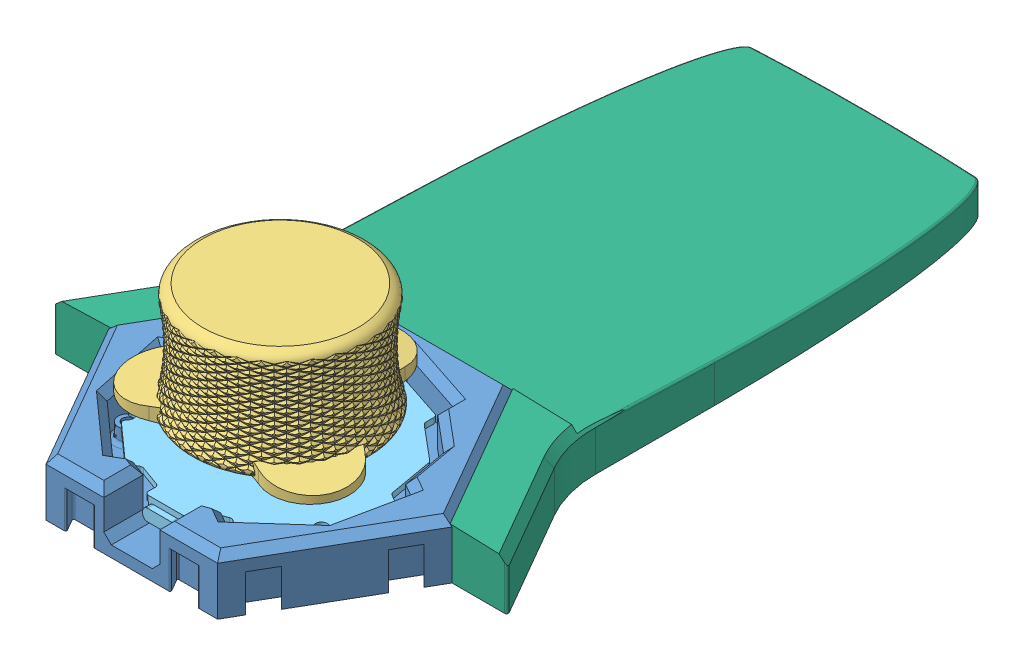
SolidWorks assembly Assembly, configuration Default. Lengths in mm.
Overall size (121.27 58.2 198.02).
6 component instances, 6 part files, 15 mates.
Components (placement in the parent):
- Base-1: Base [Default] at (5.116 33.8502 100.9363) size (92 26.6 79.67)
- FlexureMini-1: FlexureMini [Default] at (28.116 58.8502 61.0992) x (0 0 -1) z (1 0 0) size (33.19 4 40.5)
- KnobHollow-1: KnobHollow [Default] at (28.116 51.4502 61.0992) x (0 0 -1) z (1 0 0) size (56.42 29.14 58.88)
- Stem-1: Stem [Default] at (28.116 38.8502 61.0992) size (10.5 20 16.81)
- PCB-1: PCB [Default] at (5.116 42.8502 100.9363) x (1 0 0) z (0 1 0) size (60.81 62.93 4.67)
- HandRest-1: HandRest [Default] at (68.116 33.8502 -95.2739) x (-1 0 0) z (0 0 -1) size (121.27 14.28 158.18)
Mates (geometry in assembly coordinates):
- Concentric1: concentric anti-aligned: cylinder of Base-1 through (28.116 33.8502 64.0992) axis (0 1 0) radius 1.6; cylinder of FlexureMini-1 through (28.116 60.4502 64.0992) axis (0 -1 0) radius 1.7
- Concentric2: concentric anti-aligned: cylinder of Base-1 through (28.116 33.8502 58.0992) axis (0 1 0) radius 1.6; cylinder of FlexureMini-1 through (28.116 60.4502 58.0992) axis (0 -1 0) radius 1.7
- Concentric3: concentric aligned: cylinder of FlexureMini-1 through (11.366 60.4502 61.0992) axis (0 -1 0) radius 1.7; cylinder of KnobHollow-1 through (11.366 73.4502 61.0992) axis (0 -1 0) radius 1.44
- Concentric4: concentric aligned: cylinder of FlexureMini-1 through (44.866 60.4502 61.0992) axis (0 -1 0) radius 1.7; cylinder of KnobHollow-1 through (44.866 73.4502 61.0992) axis (0 -1 0) radius 1.44
- Coincident2: coincident anti-aligned: plane of FlexureMini-1 through (44.866 60.4502 61.0992) normal (0 1 0); plane of KnobHollow-1 through (28.116 60.4502 61.0992) normal (0 -1 0)
- Concentric5: concentric aligned: cylinder of Base-1 through (28.116 33.8502 58.0992) axis (0 1 0) radius 1.6; cylinder of Stem-1 through (28.116 38.8502 58.0992) axis (0 1 0) radius 1.44
- Concentric6: concentric aligned: cylinder of Base-1 through (28.116 33.8502 64.0992) axis (0 1 0) radius 1.6; cylinder of Stem-1 through (28.116 38.8502 64.0992) axis (0 1 0) radius 1.44
- Coincident3: coincident anti-aligned: plane of Base-1 through (5.116 38.8502 100.9363) normal (0 1 0); plane of Stem-1 through (28.116 38.8502 61.0992) normal (0 -1 0)
- Coincident4: coincident anti-aligned: plane of FlexureMini-1 through (28.116 58.8502 58.0992) normal (0 -1 0); plane of Stem-1 through (28.116 58.8502 61.0992) normal (0 1 0)
- Coincident5: coincident anti-aligned: plane of Base-1 through (54.0968 42.8502 76.0992) normal (0 1 0); plane of PCB-1 through (5.116 42.8502 100.9363) normal (0 -1 0)
- Concentric7: concentric aligned: cylinder of Base-1 through (28.116 33.8502 31.0992) axis (0 1 0) radius 1.44; cylinder of PCB-1 through (28.116 42.8502 31.0992) axis (0 1 0) radius 1.6
- Concentric8: concentric aligned: cylinder of Base-1 through (2.1353 33.8502 76.0992) axis (0 1 0) radius 1.44; cylinder of PCB-1 through (2.1353 42.8502 76.0992) axis (0 1 0) radius 1.6
- Coincident7: coincident anti-aligned: plane of Base-1 through (74.116 48.8502 61.0992) normal (0.866025 0 -0.5); plane of HandRest-1 through (74.116 46.8502 61.0992) normal (-0.866025 0 0.5)
- Coincident8: coincident aligned: plane of Base-1 through (5.116 33.8502 100.9363) normal (0 -1 0); plane of HandRest-1 through (68.116 33.8502 -95.2739) normal (0 -1 0)
- Coincident9: coincident anti-aligned: plane of Base-1 through (5.116 48.8502 21.262) normal (-0.866025 0 -0.5); plane of HandRest-1 through (5.116 46.8502 21.262) normal (0.866025 0 0.5)
